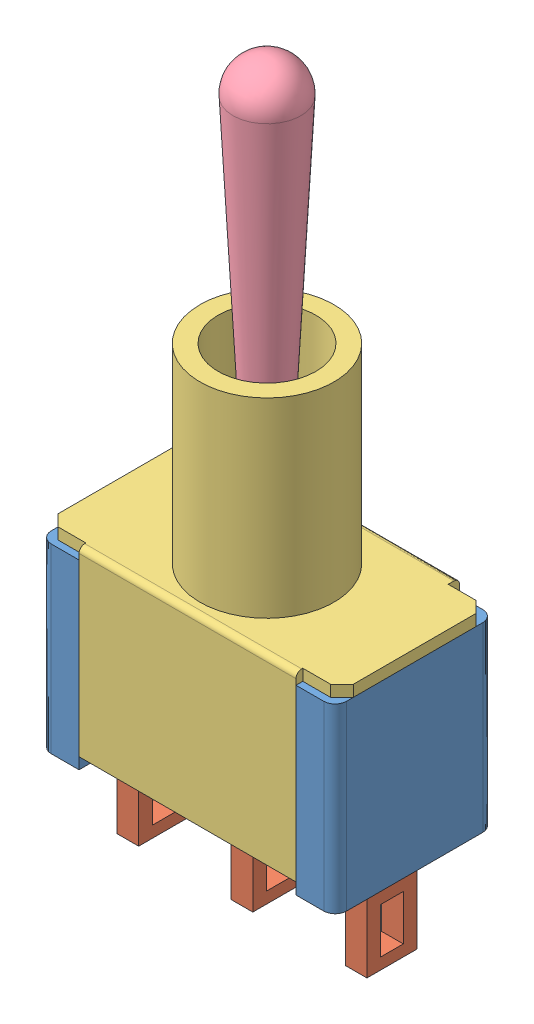
SolidWorks assembly SPDT Toggle Switch No Nuts, configuration Default. Lengths in mm.
Overall size (20.31 20.9 8.5).
6 component instances, 4 part files, 0 mates.
Components (placement in the parent):
- SPDT Toggle Switch Base-1: SPDT Toggle Switch Base [Default] at (-12.3077 3.8112 0) size (13 8 7)
- SPDT Toggle Switch Pin-1: SPDT Toggle Switch Pin [Default] at (-5.8077 -0.1888 0) x (1 0 0) z (0 -1 0) size (0.95 2.2 4)
- SPDT Toggle Switch Pin-2: SPDT Toggle Switch Pin [Default] at (-0.7827 -0.1888 0) x (1 0 0) z (0 -1 0) size (0.95 2.2 4)
- SPDT Toggle Switch Pin-3: SPDT Toggle Switch Pin [Default] at (4.2423 -0.1888 0) x (1 0 0) z (0 -1 0) size (0.95 2.2 4)
- SPDT Toggle Switch Treaded Tube-1: SPDT Toggle Switch Treaded Tube [Default] at (-18.8077 7.8112 0) x (-1 0 0) z (0 1 0) size (13 7.2 16.4)
- Toggle Switch-1: Toggle Switch [Default] at (-12.3077 12.4185 3.4998) x (1 0 0) z (0 -0.000203 1) size (3 16.79 3)
